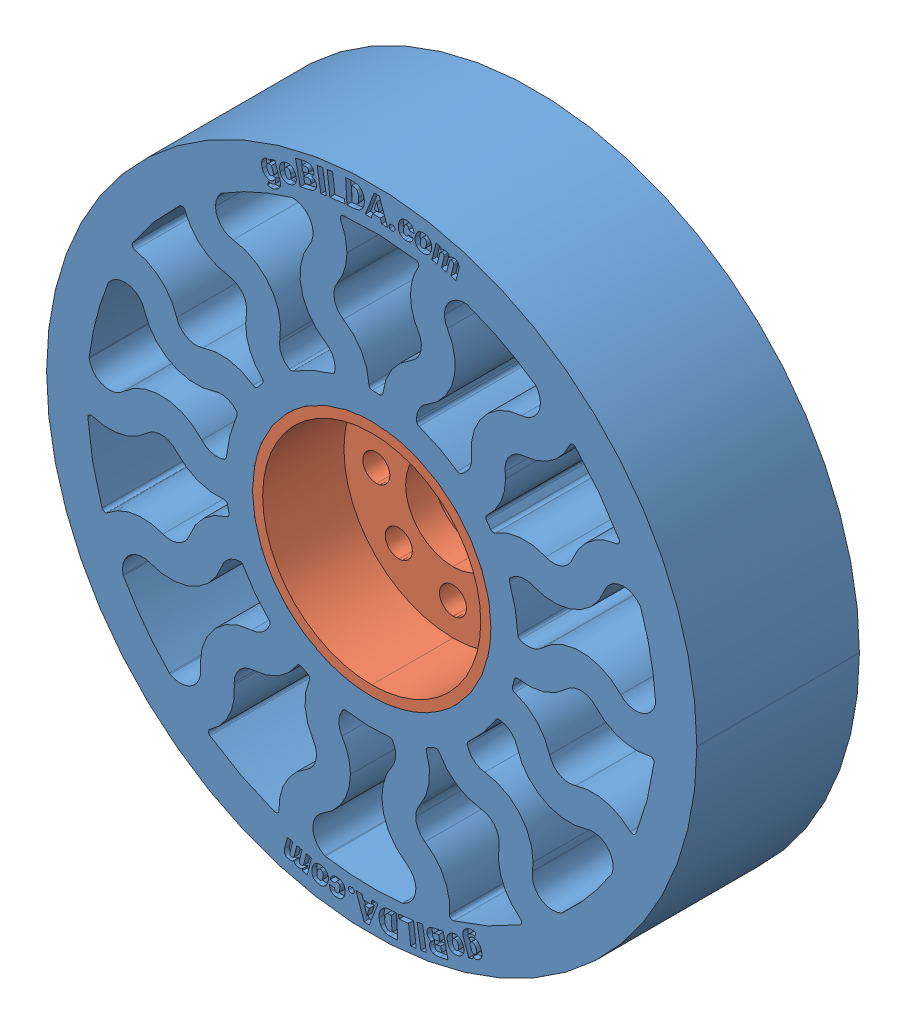
SolidWorks assembly 96mm Gecko Wheels 3613-0014-0096, configuration Default. Lengths in mm.
Overall size (96 96 24).
2 component instances, 2 part files, 0 mates.
Components (placement in the parent):
- 3613-0014-0096 Rubber.STEP-1: 3613-0014-0096 Rubber.STEP [Default] at (-5.0141 13.8433 -6.759) size (96 96 24)
- 3613-0014-0096 Core.STEP-1: 3613-0014-0096 Core.STEP [Default] at (-5.0141 13.8433 -6.759) x (1 0 0) z (0 -1 0) size (35.2 24 35.2)
